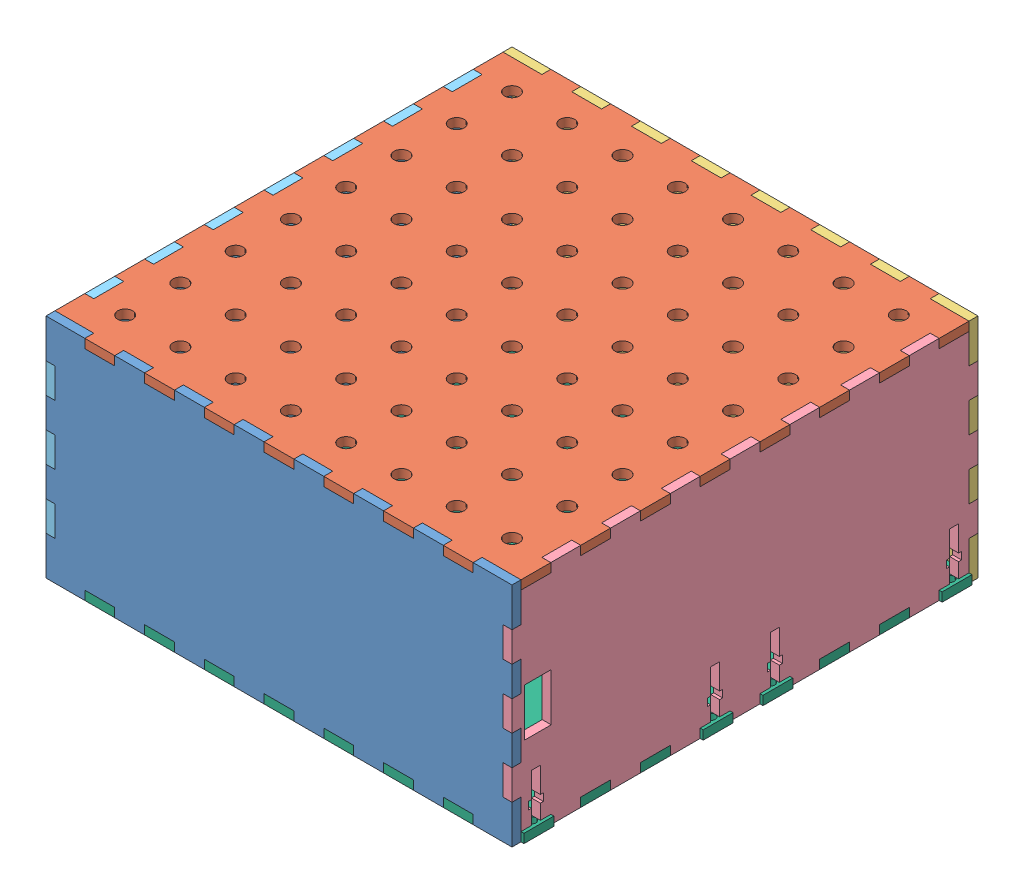
SolidWorks assembly finalDesign, configuration Default. Lengths in mm.
Overall size (158 76 156.01).
6 component instances, 6 part files, 15 mates.
Components (placement in the parent):
- base-2: base [Default] at (-33.2561 34.1297 135.2858) size (156 76 3)
- LEDfACE-2: LEDfACE [Default] at (-36.4868 104.1297 135.1674) x (1 0 0) z (0 1 0) size (156 156.01 3)
- Top-1: Top [Default] at (-33.2561 34.1297 -17.7201) size (156 76 3)
- Copy of Leftside-1: Copy of Leftside [Default] at (116.7439 34.1297 -14.7201) x (1 0 0) z (0 -1 0) size (3 156.01 76)
- Copy of rightside - Copy-1: Copy of rightside - Copy [Default] at (-36.2561 34.1297 -14.7201) x (1 0 0) z (0 -1 0) size (3 156.01 76)
- back-4: back [Default] at (-36.4868 31.1297 135.1674) x (1 0 0) z (0 1 0) size (158 156.01 3)
Mates (geometry in assembly coordinates):
- Coincident1: coincident aligned: line of base-2 through (-23.2561 107.1297 135.2858) axis (-1 0 0); line of LEDfACE-2 through (-23.2561 107.1297 135.2858) axis (-1 0 0)
- Perpendicular1: perpendicular: plane of base-2 through (-33.2561 34.1297 135.2858) normal (0 0 -1); plane of LEDfACE-2 through (-36.4868 104.1297 135.1674) normal (0 -1 0)
- Coincident3: coincident aligned: plane of base-2 through (-36.2561 34.1297 138.2858) normal (-1 0 0); plane of LEDfACE-2 through (-36.2561 107.1297 135.1674) normal (-1 0 0)
- Perpendicular2: perpendicular: plane of LEDfACE-2 through (-36.4868 104.1297 135.1674) normal (0 -1 0); plane of Top-1 through (-33.2561 34.1297 -14.7201) normal (0 0 1)
- Coincident5: coincident aligned: plane of LEDfACE-2 through (119.7439 107.1297 135.1674) normal (1 0 0); plane of Top-1 through (119.7439 34.1297 -14.7201) normal (1 0 0)
- Coincident6: coincident anti-aligned: line of LEDfACE-2 through (106.7439 107.1297 -14.7201) axis (1 0 0); line of Top-1 through (119.7439 107.1297 -14.7201) axis (-1 0 0)
- Coincident13: coincident aligned: plane of base-2 through (119.7439 34.1297 138.2858) normal (1 0 0); plane of Copy of Leftside-1 through (119.7439 34.1297 -14.7201) normal (1 0 0)
- Coincident14: coincident aligned: line of base-2 through (119.7439 107.1297 138.2858) axis (0 -1 0); line of Copy of Leftside-1 through (119.7439 94.1297 138.2858) axis (0 -1 0)
- Coincident15: coincident anti-aligned: line of LEDfACE-2 through (116.7439 107.1297 5.2858) axis (0 0 -1); line of Copy of Leftside-1 through (116.7439 107.1297 -4.7201) axis (0 0 1)
- Parallel1: parallel anti-aligned: plane of Copy of Leftside-1 through (116.7439 34.1297 -14.7201) normal (-1 0 0); plane of Copy of rightside - Copy-1 through (-33.2561 34.1297 -14.7201) normal (1 0 0)
- Coincident22: coincident aligned: line of base-2 through (-33.2561 94.1297 138.2858) axis (0 -1 0); line of Copy of rightside - Copy-1 through (-33.2561 94.1297 138.2858) axis (0 -1 0)
- Coincident24: coincident anti-aligned: plane of base-2 through (-33.2561 54.1297 138.2858) normal (0 -1 0); plane of Copy of rightside - Copy-1 through (-33.2561 54.1297 138.2858) normal (0 1 0)
- Coincident25: coincident: line of base-2 through (106.7439 34.1297 138.2858) axis (-1 0 0); line of back-4 through (106.7439 34.1297 138.2858) axis (-1 0 0)
- Perpendicular4: perpendicular: plane of base-2 through (-33.2561 34.1297 135.2858) normal (0 0 -1); plane of back-4 through (-36.4868 34.1297 135.1674) normal (0 1 0)
- Coincident27: coincident aligned: plane of Copy of Leftside-1 through (119.7439 34.1297 -14.7201) normal (1 0 0); plane of back-4 through (119.7439 34.1297 135.1674) normal (1 0 0)
